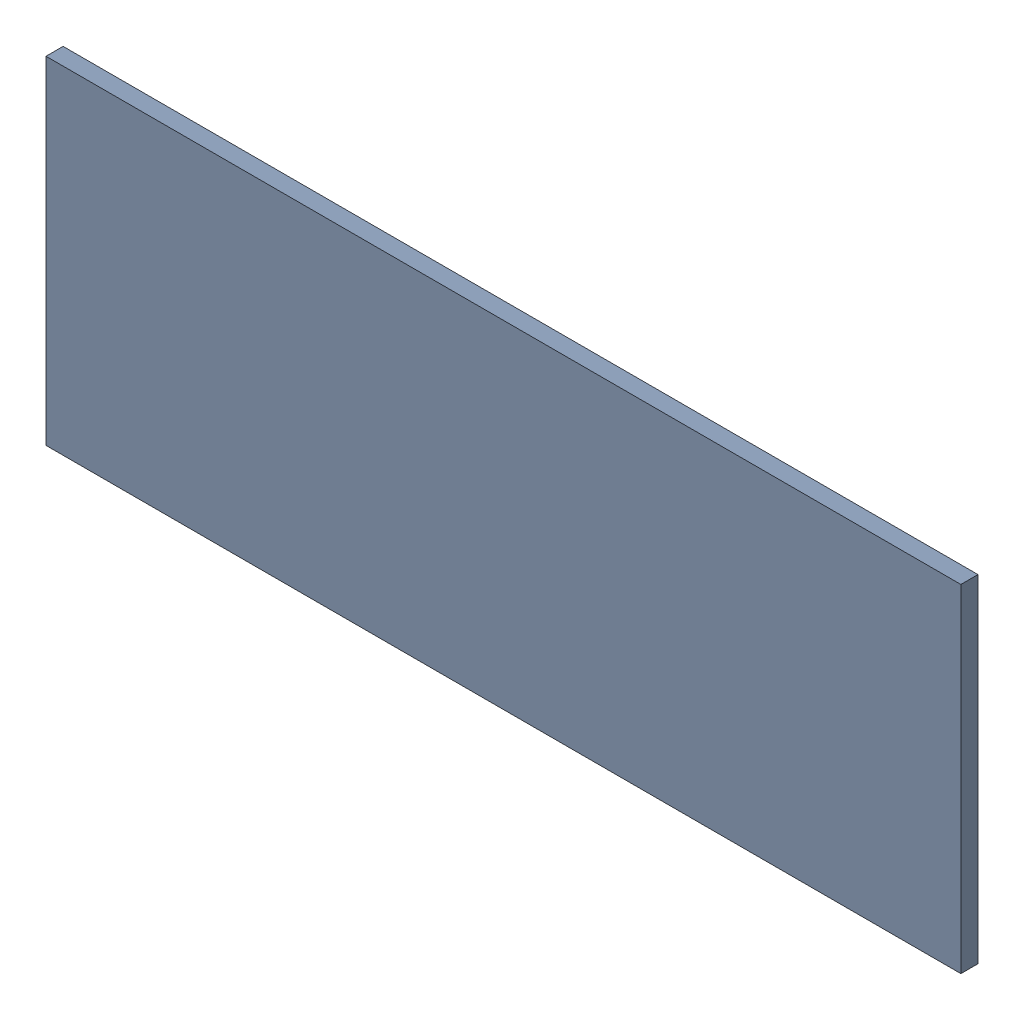
SolidWorks assembly Pad RAK4600-9(14.5mm,17.5mm) on Top Layer, configuration Predeterminado. Lengths in mm.
Overall size (1.9 0.7 0.04).
2 component instances, 1 part files, 0 mates.
Components (placement in the parent):
- Pad RAK4600-9(14.5mm,17.5mm) on Top Layer-1-1: Pad RAK4600-9(14.5mm,17.5mm) on Top Layer-1 [Predeterminado] at (-68.317 -44.187 -0.0457) size (1.9 0.7 0.04)
  - Pad RAK4600-9(14.5mm,17.5mm) on Top Layer-Part-1-1: Pad RAK4600-9(14.5mm,17.5mm) on Top Layer-Part-1 [Predeterminado] at origin size (1.9 0.7 0.04)
